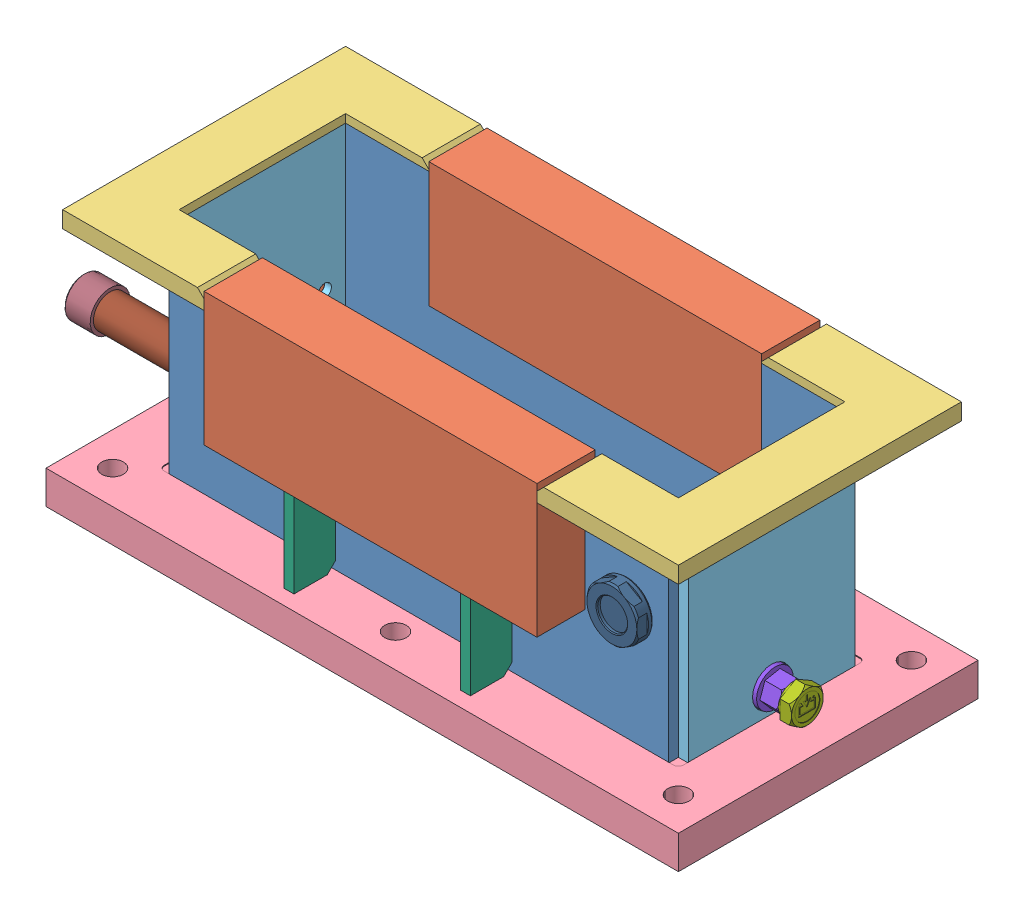
SolidWorks assembly DONJE_KUCISTE, configuration Default. Lengths in mm.
Overall size (410 154.5 180).
34 component instances, 14 part files, 54 mates.
Components (placement in the parent):
- glavni_lim-1: glavni_lim [rupa za staklo] at (0 84.5 50) x (1 0 0) z (0 -1 0) size (300 6 130)
- kockavratila-1: kockavratila [Default] at (0 114.5 50) x (1 0 0) z (0 -1 0) size (200 35 80)
- prirubnica_donja-1: prirubnica_donja [Default] at (-100 144.5 0) size (85 10 170)
- temeljna_ploca-1: temeljna_ploca [Default] at origin size (380 20 180)
- bocni_lim-2: bocni_lim [cijevni registar] at (-150 84.5 0) x (0 0 -1) z (0 1 0) size (100 6 130)
- glavni_lim-2: glavni_lim [Default] at (0 84.5 -56) x (1 0 0) z (0 -1 0) size (300 6 130)
- kockavratila-2: kockavratila [Default] at (0 114.5 -50) x (-1 0 0) z (0 -1 0) size (200 35 80)
- prirubnica_donja-2: prirubnica_donja [Default] at (100 144.5 0) x (-1 0 0) z (0 0 -1) size (85 10 170)
- bocni_lim-3: bocni_lim [irezan_ispust] at (156 84.5 0) x (0 0 1) z (0 -1 0) size (100 6 130)
- rebro-1: rebro [Default] at (-50 47.25 68.5) x (0 -1 0) z (0 0 -1) size (54.5 6 25)
- rebro-2: rebro [Default] at (50 47.25 68.5) x (0 1 0) z (0 0 -1) size (54.5 6 25)
- rebro-3: rebro [Default] at (56 47.25 -68.5) x (0 1 0) z (0 0 1) size (54.5 6 25)
- rebro-4: rebro [Default] at (-50 47.25 -68.5) x (0 1 0) z (0 0 1) size (54.5 6 25)
- Oil fill plugs TCD.10x1.5-1: Oil fill plugs TCD.10x1.5 [Default] at (161.5 34.5 0) size (16 24.13 19)
- Hexagon nut DIN 6331-M10-1: Hexagon nut DIN 6331-M10 [Default] at (154 34.5 0) x (0 -0.652064 0.758164) z (0 0.758164 0.652064) size (22 15 22)
- Brass nut GH.M26x1.5-NK-1: Brass nut GH.M26x1.5-NK [Default] at (125 88.5 50) x (0 0 1) z (-0.706547 -0.707666 0) size (3.5 33 30)
- Oil level sight glass GN 743-18-M26x1_5-A-1: Oil level sight glass GN 743-18-M26x1_5-A [Default] at (125 88.5 48) x (1 0 0) z (0 -1 0) size (32 17 32)
- Prirubnica_c.reg._sklop-1: Prirubnica_c.reg._sklop [Default] at (-142.8722 78.3632 -24.5463) x (0 0.999301 0.037387) z (0 -0.037387 0.999301) size (33.22 66 33.22)
  - prirubnica_cijevnog_registra-1: prirubnica_cijevnog_registra [Default] at (-7.5365 11.1278 62.3717) size (20 50 20)
  - Gasket DIN 7603-AL-8-11_5-A(semering registra)-1: Gasket DIN 7603-AL-8-11_5-A(semering registra) [Default] at (-7.5365 26.6278 62.3717) x (0 -1 0) z (0.887885 0 0.460066) size (1 11.4 11.4)
  - Gasket DIN 7603-AL-8-11_5-A(semering registra)-2: Gasket DIN 7603-AL-8-11_5-A(semering registra) [Default] at (-7.5365 28.6278 62.3717) x (0 -1 0) z (-0.546944 0 0.837169) size (1 11.4 11.4)
  - Gasket DIN 7603-AL-8-11_5-A(semering registra)-3: Gasket DIN 7603-AL-8-11_5-A(semering registra) [Default] at (-7.5365 29.6278 62.3717) x (0 1 0) z (-0.564882 0 -0.825172) size (1 11.4 11.4)
  - Gasket DIN 7603-AL-8-11_5-A(semering registra)-4: Gasket DIN 7603-AL-8-11_5-A(semering registra) [Default] at (-7.5365 30.6278 62.3717) x (0 1 0) z (-0.564882 0 -0.825172) size (1 11.4 11.4)
  - Gasket DIN 7603-AL-8-11_5-A(semering registra)-5: Gasket DIN 7603-AL-8-11_5-A(semering registra) [Default] at (-7.5365 27.6278 62.3717) x (0 -1 0) z (-0.546944 0 0.837169) size (1 11.4 11.4)
  - M16x30-1: M16x30 [Default] at (-7.5365 77.1278 62.3717) x (0 -1 0) z (-0.546944 0 0.837169) size (46 24 24)
- Prirubnica_c.reg._sklop-2: Prirubnica_c.reg._sklop [Default] at (-142.8722 84.718 -98.196) x (0 0.990097 0.140386) z (0 -0.140386 0.990097) size (33.22 66 33.22)
  - prirubnica_cijevnog_registra-1: prirubnica_cijevnog_registra [Default] at (-7.5365 11.1278 62.3717) size (20 50 20)
  - Gasket DIN 7603-AL-8-11_5-A(semering registra)-1: Gasket DIN 7603-AL-8-11_5-A(semering registra) [Default] at (-7.5365 26.6278 62.3717) x (0 -1 0) z (0.887885 0 0.460066) size (1 11.4 11.4)
  - Gasket DIN 7603-AL-8-11_5-A(semering registra)-2: Gasket DIN 7603-AL-8-11_5-A(semering registra) [Default] at (-7.5365 28.6278 62.3717) x (0 -1 0) z (-0.546944 0 0.837169) size (1 11.4 11.4)
  - Gasket DIN 7603-AL-8-11_5-A(semering registra)-3: Gasket DIN 7603-AL-8-11_5-A(semering registra) [Default] at (-7.5365 29.6278 62.3717) x (0 1 0) z (-0.564882 0 -0.825172) size (1 11.4 11.4)
  - Gasket DIN 7603-AL-8-11_5-A(semering registra)-4: Gasket DIN 7603-AL-8-11_5-A(semering registra) [Default] at (-7.5365 30.6278 62.3717) x (0 1 0) z (-0.564882 0 -0.825172) size (1 11.4 11.4)
  - Gasket DIN 7603-AL-8-11_5-A(semering registra)-5: Gasket DIN 7603-AL-8-11_5-A(semering registra) [Default] at (-7.5365 27.6278 62.3717) x (0 -1 0) z (-0.546944 0 0.837169) size (1 11.4 11.4)
  - M16x30-1: M16x30 [Default] at (-7.5365 77.1278 62.3717) x (0 -1 0) z (-0.546944 0 0.837169) size (46 24 24)
- unutarnji lim-1: unutarnji lim [Default] at (-1.7035 28.2254 0) x (0.99863 -0.052336 0) z (0 0 -1) size (296.96 17.98 100)
Mates (geometry in assembly coordinates):
- Coincident1: coordinate: point of temeljna_ploca-1
- Coincident3: coincident anti-aligned: plane of temeljna_ploca-1 through (-156 19.5 53) normal (1 0 0); plane of bocni_lim-2 through (-156 84.5 0) normal (-1 0 0)
- Coincident6: coincident aligned: plane of temeljna_ploca-1 through (-150 19.5 -50) normal (0 0 -1); plane of bocni_lim-2 through (-156 149.5 -50) normal (0 0 -1)
- Coincident7: coincident anti-aligned: plane of temeljna_ploca-1 through (153 19.5 -53) normal (0 1 0); plane of bocni_lim-2 through (-156 19.5 50) normal (0 -1 0)
- Coincident8: coincident anti-aligned: plane of glavni_lim-1 through (-150 19.5 56) normal (0 -1 0); plane of temeljna_ploca-1 through (153 19.5 -53) normal (0 1 0)
- Coincident9: coincident aligned: plane of glavni_lim-1 through (150 19.5 56) normal (1 0 0); plane of temeljna_ploca-1 through (150 19.5 50) normal (1 0 0)
- Coincident10: coincident anti-aligned: plane of glavni_lim-1 through (-150 19.5 56) normal (0 -1 0); plane of temeljna_ploca-1 through (153 19.5 -53) normal (0 1 0)
- Coincident11: coincident anti-aligned: plane of glavni_lim-1 through (0 84.5 50) normal (0 0 -1); plane of temeljna_ploca-1 through (-150 19.5 50) normal (0 0 1)
- Coincident12: coincident anti-aligned: plane of temeljna_ploca-1 through (153 19.5 -53) normal (0 1 0); plane of glavni_lim-2 through (-150 19.5 -50) normal (0 -1 0)
- Coincident14: coincident aligned: plane of temeljna_ploca-1 through (150 19.5 50) normal (1 0 0); plane of glavni_lim-2 through (150 19.5 -50) normal (1 0 0)
- Coincident15: coincident anti-aligned: plane of temeljna_ploca-1 through (-153 19.5 -56) normal (0 0 1); plane of glavni_lim-2 through (0 84.5 -56) normal (0 0 -1)
- Coincident16: coincident anti-aligned: plane of prirubnica_donja-1 through (-156 144.5 56.7) normal (1 0 0); plane of bocni_lim-2 through (-156 84.5 0) normal (-1 0 0)
- Coincident17: coincident anti-aligned: plane of prirubnica_donja-1 through (-150 149.5 56.7) normal (0 -1 0); plane of bocni_lim-2 through (-156 149.5 50) normal (0 1 0)
- Coincident18: coincident aligned: plane of glavni_lim-1 through (-100 149.5 56) normal (1 0 0); plane of prirubnica_donja-1 through (-100 154.5 85) normal (1 0 0)
- Coincident19: coincident anti-aligned: plane of prirubnica_donja-1 through (-156.7 144.5 -56) normal (0 0 1); plane of glavni_lim-2 through (0 84.5 -56) normal (0 0 -1)
- Coincident21: coincident anti-aligned: plane of glavni_lim-1 through (100 79.5 56) normal (0 1 0); plane of kockavratila-1 through (100 79.5 50) normal (0 -1 0)
- Coincident22: coincident anti-aligned: plane of glavni_lim-1 through (100 149.5 56) normal (-1 0 0); plane of kockavratila-1 through (100 74.5 85) normal (1 0 0)
- Coincident23: coincident anti-aligned: plane of glavni_lim-1 through (0 84.5 56) normal (0 0 1); plane of kockavratila-1 through (100 74.5 56) normal (0 0 -1)
- Coincident25: coincident anti-aligned: plane of glavni_lim-2 through (0 84.5 -56) normal (0 0 -1); plane of kockavratila-2 through (-100 74.5 -56) normal (0 0 1)
- Coincident26: coincident anti-aligned: plane of prirubnica_donja-1 through (-100 154.5 -50) normal (1 0 0); plane of kockavratila-2 through (-100 74.5 -85) normal (-1 0 0)
- Coincident27: coincident anti-aligned: plane of glavni_lim-2 through (100 79.5 -50) normal (0 1 0); plane of kockavratila-2 through (-100 79.5 -50) normal (0 -1 0)
- Coincident28: coincident anti-aligned: plane of temeljna_ploca-1 through (153 19.5 -53) normal (0 1 0); plane of bocni_lim-3 through (150 19.5 -50) normal (0 -1 0)
- Coincident29: coincident anti-aligned: plane of temeljna_ploca-1 through (150 19.5 50) normal (1 0 0); plane of bocni_lim-3 through (150 84.5 0) normal (-1 0 0)
- Coincident30: coincident anti-aligned: plane of glavni_lim-1 through (0 84.5 50) normal (0 0 -1); plane of bocni_lim-3 through (150 19.5 50) normal (0 0 1)
- Coincident31: coincident anti-aligned: plane of kockavratila-2 through (100 74.5 -85) normal (1 0 0); plane of prirubnica_donja-2 through (100 154.5 -85) normal (-1 0 0)
- Coincident32: coincident anti-aligned: plane of prirubnica_donja-2 through (150 149.5 -56.7) normal (0 -1 0); plane of bocni_lim-3 through (150 149.5 -50) normal (0 1 0)
- Coincident33: coincident anti-aligned: plane of glavni_lim-2 through (0 84.5 -56) normal (0 0 -1); plane of prirubnica_donja-2 through (99 144.5 -56) normal (0 0 1)
- Coincident39: coincident anti-aligned: plane of kockavratila-1 through (-100 74.5 85) normal (0 -1 0); plane of rebro-1 through (-56 74.5 61) normal (0 1 0)
- Coincident40: coincident anti-aligned: plane of glavni_lim-1 through (0 84.5 56) normal (0 0 1); plane of rebro-1 through (-56 69.5 56) normal (0 0 -1)
- Distance1: distance = 50 mm: plane of rebro-1 through (-50 47.25 68.5) normal (1 0 0); cylinder of temeljna_ploca-1 through (0 0 70) axis (0 1 0) radius 6.5
- Coincident42: coincident anti-aligned: plane of glavni_lim-1 through (0 84.5 56) normal (0 0 1); plane of rebro-2 through (56 25 56) normal (0 0 -1)
- Coincident43: coincident anti-aligned: plane of temeljna_ploca-1 through (0 20 0) normal (0 1 0); plane of rebro-2 through (56 20 61) normal (0 -1 0)
- Distance2: distance = 100 mm anti-aligned: plane of rebro-1 through (-50 47.25 68.5) normal (1 0 0); plane of rebro-2 through (50 47.25 68.5) normal (-1 0 0)
- Coincident45: coincident anti-aligned: plane of glavni_lim-2 through (0 84.5 -56) normal (0 0 -1); plane of rebro-4 through (-56 25 -56) normal (0 0 1)
- Coincident46: coincident aligned: plane of rebro-1 through (-56 47.25 68.5) normal (-1 0 0); plane of rebro-4 through (-56 47.25 -68.5) normal (-1 0 0)
- Coincident47: coincident anti-aligned: plane of temeljna_ploca-1 through (0 20 0) normal (0 1 0); plane of rebro-4 through (-56 20 -61) normal (0 -1 0)
- Coincident48: coincident anti-aligned: plane of glavni_lim-2 through (0 84.5 -56) normal (0 0 -1); plane of rebro-3 through (50 25 -56) normal (0 0 1)
- Coincident49: coincident aligned: plane of rebro-2 through (50 47.25 68.5) normal (-1 0 0); plane of rebro-3 through (50 47.25 -68.5) normal (-1 0 0)
- Coincident50: coincident anti-aligned: plane of temeljna_ploca-1 through (0 20 0) normal (0 1 0); plane of rebro-3 through (50 20 -61) normal (0 -1 0)
- Concentric1: concentric anti-aligned: circle of bocni_lim-3; circle of Hexagon nut DIN 6331-M10-1
- Coincident52: coincident anti-aligned: plane of Oil fill plugs TCD.10x1.5-1 through (169 39.5 0) normal (-1 0 0); plane of Hexagon nut DIN 6331-M10-1 through (169 34.5 0) normal (1 0 0)
- Concentric2: concentric anti-aligned: circle of Oil fill plugs TCD.10x1.5-1; circle of Hexagon nut DIN 6331-M10-1
- Coincident53: coincident anti-aligned: plane of glavni_lim-1 through (0 84.5 56) normal (0 0 1); plane of Oil level sight glass GN 743-18-M26x1_5-A-1 through (140.25 88.5 56) normal (0 0 -1)
- Concentric3: concentric anti-aligned: circle of glavni_lim-1; circle of Oil level sight glass GN 743-18-M26x1_5-A-1
- Coincident54: coincident anti-aligned: plane of glavni_lim-1 through (0 84.5 50) normal (0 0 -1); plane of Brass nut GH.M26x1.5-NK-1 through (115.8003 97.6851 50) normal (0 0 1)
- Concentric4: concentric anti-aligned: circle of Brass nut GH.M26x1.5-NK-1; circle of Oil level sight glass GN 743-18-M26x1_5-A-1
- Coincident55: coincident anti-aligned: plane of bocni_lim-3 through (154 34.5 0) normal (1 0 0); plane of Hexagon nut DIN 6331-M10-1 through (154 27.3273 8.3398) normal (-1 0 0)
- Concentric5: concentric anti-aligned: circle of bocni_lim-2; circle of Prirubnica_c.reg._sklop-2/prirubnica_cijevnog_registra-1
- Coincident56: coincident anti-aligned: plane of bocni_lim-2 through (-154 68.5 -37.5) normal (-1 0 0); plane of Prirubnica_c.reg._sklop-2/prirubnica_cijevnog_registra-1 through (-154 68.5 -37.5) normal (1 0 0)
- Concentric6: concentric aligned: circle of bocni_lim-2; circle of Prirubnica_c.reg._sklop-1/prirubnica_cijevnog_registra-1
- Coincident58: coincident anti-aligned: plane of bocni_lim-2 through (-154 68.5 37.5) normal (-1 0 0); plane of Prirubnica_c.reg._sklop-1/prirubnica_cijevnog_registra-1 through (-154 68.5 37.5) normal (1 0 0)
- Coincident59: coincident anti-aligned: plane of glavni_lim-1 through (0 84.5 50) normal (0 0 -1); plane of unutarnji lim-1 through (-149.8953 37.9945 50) normal (0 0 1)
- Coincident60: coincident anti-aligned: plane of bocni_lim-2 through (-150 84.5 0) normal (1 0 0); plane of unutarnji lim-1 through (-150 28.1206 0) normal (-1 0 0)
- Coincident61: coincident anti-aligned: plane of temeljna_ploca-1 through (0 20 0) normal (0 1 0); plane of unutarnji lim-1 through (-150 20 50) normal (0 -1 0)
